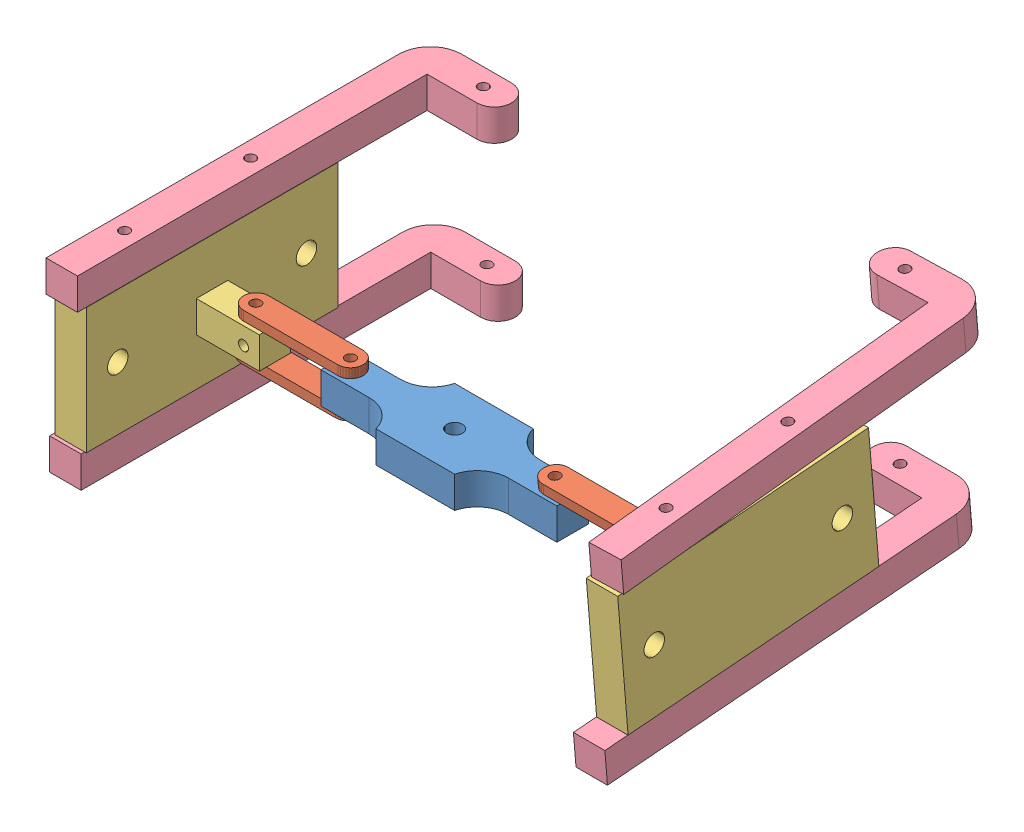
SolidWorks assembly Grapper, configuration Default. Lengths in mm.
Overall size (172.7 70.58 133.06).
10 component instances, 4 part files, 8 mates.
Components (placement in the parent):
- EV3 Plate-1: EV3 Plate [Default] at (44.0517 43.7531 45.9616) size (75 10 25)
- GRip Linker-1: GRip Linker [Default] at (-41.0661 48.7531 52.9797) size (38 3 8)
- GRip Linker-2: GRip Linker [Default] at (54.3385 49.4126 53.0223) x (1 0 0) z (0 -0.082442 0.996596) size (38 3 8)
- Side PLate2-1: Side PLate2 [Default] at (-60.813 -1042.3339 778.9875) x (1 0 0) z (0 1 0) size (30 80 40)
- GRip Linker-3: GRip Linker [Default] at (-42.8644 35.7531 51.9896) size (38 3 8)
- Leg-1: Leg [Default] at (-2.7724 73.7531 -4.4162) x (1 0 0) z (0 0 -1) size (31.36 10 122.15)
- Leg-2: Leg [Default] at (-3.1835 23.7531 -5.9897) x (1 0 0) z (0 0 -1) size (31.36 10 122.15)
- Side PLate2-2: Side PLate2 [Default] at (110.8264 -978.1118 -760.401) x (-1 0 0) z (0 0.996596 0.082442) size (30 80 40)
- Leg-3: Leg [Default] at (52.6069 19.5796 -10.8832) x (-1 -0.000006 0.000076) z (-0.000076 0.082442 -0.996596) size (31.36 10 122.15)
- Leg-4: Leg [Default] at (50.5265 69.9979 -13.8751) x (-0.999657 -0.002158 0.026088) z (-0.026177 0.082414 -0.996254) size (31.36 10 122.15)
Mates (geometry in assembly coordinates):
- Coincident17: coincident anti-aligned: plane of EV3 Plate-1 through (44.0517 38.7531 45.9616) normal (0 -1 0); plane of GRip Linker-3 through (-42.8644 38.7531 51.9896) normal (0 1 0)
- Coincident18: coincident anti-aligned: plane of Side PLate2-1 through (-30.813 38.7531 52.2484) normal (0 -1 0); plane of GRip Linker-3 through (-42.8644 38.7531 51.9896) normal (0 1 0)
- Coincident19: coincident anti-aligned: plane of Side PLate2-1 through (-50.813 63.7531 17.2484) normal (0 1 0); plane of Leg-1 through (-35.048 63.7531 -16.7021) normal (0 -1 0)
- Coincident20: coincident anti-aligned: plane of Side PLate2-1 through (-50.813 23.7531 17.2484) normal (0 -1 0); plane of Leg-2 through (-35.4591 23.7531 -18.2756) normal (0 1 0)
- Coincident21: coincident anti-aligned: plane of GRip Linker-2 through (54.3385 49.4126 53.0223) normal (0 -0.996596 -0.082442); plane of Side PLate2-2 through (80.8264 49.347 53.8158) normal (0 0.996596 0.082442)
- Coincident23: coincident anti-aligned: plane of Side PLate2-2 through (100.8264 21.5466 86.6356) normal (0 -0.996596 -0.082442); plane of Leg-3 through (84.8816 30.5586 -22.3053) normal (0 0.996596 0.082442)
- Coincident24: coincident: plane of EV3 Plate-1 through (44.0517 48.7531 45.9616) normal (0 1 0); line of GRip Linker-2 through (88.3385 48.7531 60.9951) axis (-1 0 0)
- Coincident26: coincident anti-aligned: plane of Side PLate2-2 through (100.8264 61.4104 89.9332) normal (0 0.996596 0.082442); plane of Leg-4 through (82.4694 71.08 -26.957) normal (0 -0.996596 -0.082442)
